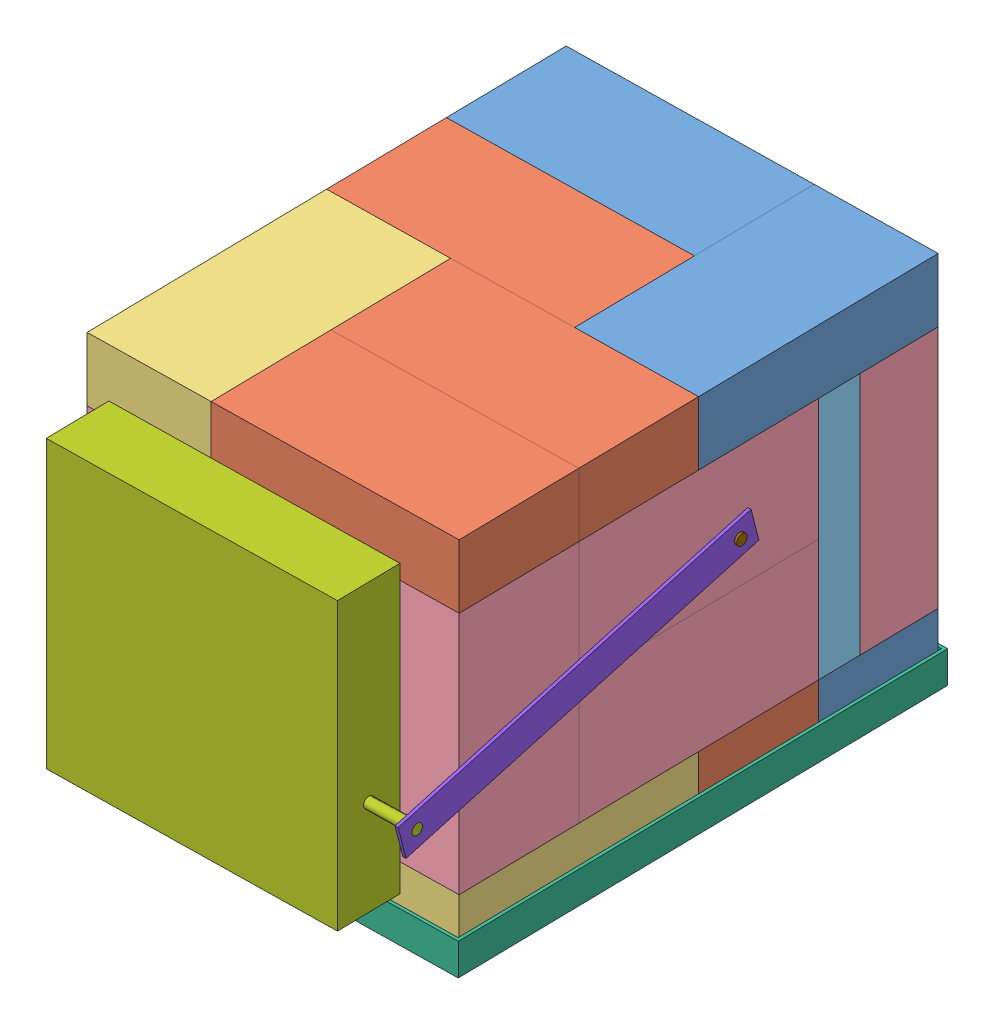
SolidWorks assembly Final Assembly, configuration Default. Lengths in mm.
Overall size (369.86 353 549.33).
32 component instances, 9 part files, 19 mates.
Components (placement in the parent):
- Bottom-top-uncut-2: Bottom-top-uncut [Default] at (285.3321 374.1769 504.8697) size (352.98 75 465.95)
  - Brick-Sharp-BackLeftCut-1: Brick-Sharp-BackLeftCut [Default] at (-84.1473 -135.3254 -303.3983) x (-0.999848 0 0.017452) z (-0.017452 0 -0.999848) size (230 75 115)
  - Brick-Sharp-BackCut-1: Brick-Sharp-BackCut [Default] at (-82.1403 -135.3254 -188.4158) x (-0.999848 0 0.017452) z (-0.017452 0 -0.999848) size (230 75 115)
  - Brick-Sharp-BackLeftCut-2: Brick-Sharp-BackLeftCut [Default] at (-255.6175 -135.3254 -242.8965) x (0.017452 0 0.999848) z (-0.999848 0 0.017452) size (230 75 115)
  - Brick-Sharp-BackCut-2: Brick-Sharp-BackCut [Default] at (-195.1157 -135.3254 -71.4263) x (0.999848 0 -0.017452) z (0.017452 0 0.999848) size (230 75 115)
  - Brick-Sharp-BackCut-3: Brick-Sharp-BackCut [Default] at (-193.1087 -135.3254 43.5562) x (0.999848 0 -0.017452) z (0.017452 0 0.999848) size (230 75 115)
  - Brick-Sharp-SideCut-1: Brick-Sharp-SideCut [Default] at (-21.6385 -135.3254 -16.9456) x (0.017452 0 0.999848) z (-0.999848 0 0.017452) size (230 75 115)
- Side Wall ext-1: Side Wall ext [Default] at (14.7352 376.3515 549.7785) x (0.99981 0.008727 -0.017452) z (0.017452 0 0.999848) size (77 230.65 385)
  - Brick-Whole-1: Brick-Whole [Default] x (-0.008727 -0.999962 0) z (0 0 1) size (230 75 115)
  - Brick-Whole-2: Brick-Whole [Default] at (0.5018 57.4978 -172.5) x (0 0 1) z (0.008727 0.999962 0) size (230 75 115)
  - Brick-Whole-3: Brick-Whole [Default] at (-0.5018 -57.4978 -172.5) x (0 0 1) z (0.008727 0.999962 0) size (230 75 115)
  - Brick-Whole-trimmed-1: Brick-Whole-trimmed [Default] at (0 0 -307.5) x (-0.008727 -0.999962 0) z (0 0 1) size (230 75 40)
- Side Wall ext-2: Side Wall ext [Default] at (284.6941 376.3515 545.0664) x (0.99981 0.008727 -0.017452) z (0.017452 0 0.999848) size (77 230.65 385)
  - Brick-Whole-1: Brick-Whole [Default] x (-0.008727 -0.999962 0) z (0 0 1) size (230 75 115)
  - Brick-Whole-2: Brick-Whole [Default] at (0.5018 57.4978 -172.5) x (0 0 1) z (0.008727 0.999962 0) size (230 75 115)
  - Brick-Whole-3: Brick-Whole [Default] at (-0.5018 -57.4978 -172.5) x (0 0 1) z (0.008727 0.999962 0) size (230 75 115)
  - Brick-Whole-trimmed-1: Brick-Whole-trimmed [Default] at (0 0 -307.5) x (-0.008727 -0.999962 0) z (0 0 1) size (230 75 40)
- Side Wall-1: Side Wall [Default] at (258.327 376.3515 180.471) x (-0.017452 0.008727 -0.99981) z (0.999848 0 -0.017452) size (77 230.65 345)
  - Brick-Whole-1: Brick-Whole [Default] x (-0.008727 -0.999962 0) z (0 0 1) size (230 75 115)
  - Brick-Whole-2: Brick-Whole [Default] at (0.5018 57.4978 -172.5) x (0 0 1) z (0.008727 0.999962 0) size (230 75 115)
  - Brick-Whole-3: Brick-Whole [Default] at (-0.5018 -57.4978 -172.5) x (0 0 1) z (0.008727 0.999962 0) size (230 75 115)
- Bottom-top-uncut-3: Bottom-top-uncut [Default] at (12.6947 378.5261 509.6286) x (-0.999391 0 0.034899) z (0.034899 0 0.999391) size (352.98 75 465.95)
  - Brick-Sharp-BackLeftCut-1: Brick-Sharp-BackLeftCut [Default] at (-84.1473 -135.3254 -303.3983) x (-0.999848 0 0.017452) z (-0.017452 0 -0.999848) size (230 75 115)
  - Brick-Sharp-BackCut-1: Brick-Sharp-BackCut [Default] at (-82.1403 -135.3254 -188.4158) x (-0.999848 0 0.017452) z (-0.017452 0 -0.999848) size (230 75 115)
  - Brick-Sharp-BackLeftCut-2: Brick-Sharp-BackLeftCut [Default] at (-255.6175 -135.3254 -242.8965) x (0.017452 0 0.999848) z (-0.999848 0 0.017452) size (230 75 115)
  - Brick-Sharp-BackCut-2: Brick-Sharp-BackCut [Default] at (-195.1157 -135.3254 -71.4263) x (0.999848 0 -0.017452) z (0.017452 0 0.999848) size (230 75 115)
  - Brick-Sharp-BackCut-3: Brick-Sharp-BackCut [Default] at (-193.1087 -135.3254 43.5562) x (0.999848 0 -0.017452) z (0.017452 0 0.999848) size (230 75 115)
  - Brick-Sharp-SideCut-1: Brick-Sharp-SideCut [Default] at (-21.6385 -135.3254 -16.9456) x (0.017452 0 0.999848) z (-0.999848 0 0.017452) size (230 75 115)
- Base Frame-1: Base Frame [Default] at (146.2129 198.3515 375.4574) x (-0.017452 0 -0.999848) z (0.999848 0 -0.017452) size (470 30 355)
- Door-2: Door [Default] at (151.4254 387.9019 645.4337) x (0.999848 0 -0.017452) z (0.017452 0 0.999848) size (315 270 75)
- Hinge-1: Hinge [Default] at (327.3257 382.9682 494.9387) x (0.999848 0 -0.017452) z (0.016896 -0.250414 0.967991) size (3 30 350)
- pin-1: pin [Default] at (313.1241 423.0345 340.2608) x (0.999848 0 -0.017452) z (-0.016026 -0.39595 -0.918132) size (15 10 10)
Mates (geometry in assembly coordinates):
- Coincident1: coincident aligned: line of Bottom-top-uncut-2/Brick-Sharp-BackLeftCut-1 through (315.1638 261.3515 141.9732) axis (-0.999848 0 0.017452); line of Side Wall-1/Brick-Whole-3 through (200.1813 261.3515 143.9802) axis (-0.999848 0 0.017452)
- Coincident2: coincident anti-aligned: line of Bottom-top-uncut-2/Brick-Sharp-BackLeftCut-1 through (317.1708 261.3515 256.9557) axis (-0.017452 0 -0.999848); line of Side Wall-1/Brick-Whole-1 through (315.1638 261.3515 141.9732) axis (0.017452 0 0.999848)
- Coincident3: coincident anti-aligned: plane of Side Wall ext-2/Brick-Whole-trimmed-1 through (316.4727 491.3515 216.9618) normal (-0.017452 0 -0.999848); plane of Side Wall-1/Brick-Whole-1 through (258.9815 376.3515 217.9653) normal (0.017452 0 0.999848)
- Coincident5: coincident aligned: line of Bottom-top-uncut-2/Brick-Sharp-BackCut-1 through (319.1778 261.3515 371.9382) axis (-0.017452 0 -0.999848); line of Side Wall ext-2/Brick-Whole-3 through (321.1849 261.3515 486.9206) axis (-0.017452 0 -0.999848)
- Coincident6: coincident anti-aligned: plane of Bottom-top-uncut-2/Brick-Sharp-BackCut-2 through (90.2164 261.3515 433.4435) normal (0 1 0); plane of Side Wall ext-1/Brick-Whole-3 through (47.2119 261.3515 261.6678) normal (0 -1 0)
- Coincident7: coincident aligned: line of Side Wall ext-1/Brick-Whole-2 through (-27.7766 491.3515 262.9768) axis (0.017452 0 0.999848); line of Side Wall-1/Brick-Whole-2 through (-29.7837 491.3515 147.9943) axis (0.017452 0 0.999848)
- Coincident8: coincident anti-aligned: line of Bottom-top-uncut-2/Brick-Sharp-BackCut-3 through (-21.7556 261.3515 607.9242) axis (0.999848 0 -0.017452); line of Side Wall ext-1/Brick-Whole-1 through (53.233 261.3515 606.6153) axis (-0.999848 0 0.017452)
- Coincident9: coincident anti-aligned: plane of Side Wall-1/Brick-Whole-1 through (200.1813 491.3515 143.9802) normal (0 1 0); plane of Bottom-top-uncut-3/Brick-Sharp-BackLeftCut-1 through (86.2023 491.3515 203.4785) normal (0 -1 0)
- Coincident10: coincident aligned: line of Side Wall ext-1/Brick-Whole-1 through (53.233 491.3515 606.6153) axis (-0.999848 0 0.017452); line of Bottom-top-uncut-3/Brick-Sharp-SideCut-1 through (53.233 491.3515 606.6153) axis (-0.999848 0 0.017452)
- Coincident11: coincident anti-aligned: line of Side Wall ext-1/Brick-Whole-1 through (-23.7626 491.3515 492.9417) axis (0.017452 0 0.999848); line of Bottom-top-uncut-3/Brick-Sharp-SideCut-1 through (-21.7556 491.3515 607.9242) axis (-0.017452 0 -0.999848)
- Coincident12: coincident aligned: line of Side Wall ext-2/Brick-Whole-2 through (317.1708 491.3515 256.9557) axis (0.017452 0 0.999848); line of Bottom-top-uncut-3/Brick-Sharp-BackCut-2 through (319.1778 491.3515 371.9382) axis (0.017452 0 0.999848)
- Coincident13: coincident anti-aligned: plane of Bottom-top-uncut-2/Brick-Sharp-BackLeftCut-2 through (29.7146 201.3515 261.9732) normal (0 -1 0); plane of Base Frame-1 through (146.2129 201.3515 375.4574) normal (0 1 0)
- Distance1: distance = 2.5 mm anti-aligned: plane of Base Frame-1 through (-32.3095 228.3515 146.5381) normal (0.999848 0 -0.017452); plane of Bottom-top-uncut-2/Brick-Sharp-BackCut-3 through (-23.7626 276.3515 492.9417) normal (-0.999848 0 0.017452)
- Distance2: distance = 2.5 mm anti-aligned: plane of Base Frame-1 through (-24.2116 228.3515 610.4675) normal (-0.017452 0 -0.999848); plane of Bottom-top-uncut-2/Brick-Sharp-BackCut-3 through (-21.7556 276.3515 607.9242) normal (0.017452 0 0.999848)
- Concentric1: concentric aligned: circle of Door-2; circle of Hinge-1
- Coincident17: coincident aligned: plane of Door-2 through (331.5289 342.9019 649.7911) normal (0.999848 0 -0.017452); plane of Hinge-1 through (328.8255 382.9682 494.9125) normal (0.999848 0 -0.017452)
- Concentric2: concentric aligned: circle of Hinge-1; circle of pin-1
- Parallel2: parallel anti-aligned: plane of Bottom-top-uncut-3/Brick-Sharp-BackCut-3 through (323.1919 476.3515 601.9031) normal (0.017452 0 0.999848); plane of Door-2 through (150.771 387.9019 607.9394) normal (-0.017452 0 -0.999848)
- Coincident24: coincident anti-aligned: plane of Side Wall ext-2/Brick-Whole-1 through (247.1998 376.3515 545.7208) normal (-0.999848 0 0.017452); plane of Door-2 through (248.5179 487.9019 621.2355) normal (0.999848 0 -0.017452)
